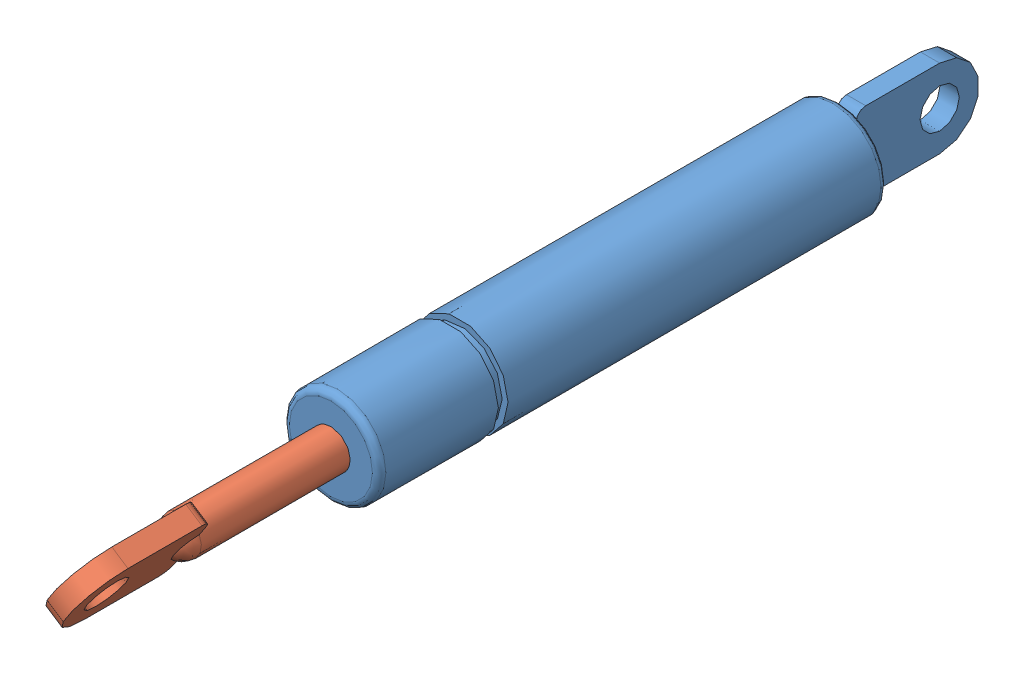
SolidWorks assembly gswb-4146-11_undefined, configuration Default. Lengths in mm.
Overall size (16.74 16.79 141.3).
2 component instances, 2 part files, 2 mates.
Components (placement in the parent):
- gswb-4146-11_undefined_01-1: gswb-4146-11_undefined_01 [Default] at (10.2534 -3.0103 7.33) size (15 15 99.1)
- gswb-4146-11_undefined_02-1: gswb-4146-11_undefined_02 [Default] at (10.2534 -3.0103 -9.5721) x (0.834638 -0.550799 0) z (0 0 1) size (12 12.2 84.6)
Mates (geometry in assembly coordinates):
- Concentric1: concentric anti-aligned: cylinder of gswb-4146-11_undefined_01-1 through (10.2534 -3.0103 8.33) axis (0 0 -1) radius 3; cylinder of gswb-4146-11_undefined_02-1 through (10.2534 -3.0103 33.4279) axis (0 0 1) radius 3
- LimitDistance1: limit distance = 36.5479 mm aligned: plane of gswb-4146-11_undefined_02-1 through (10.2534 -3.0103 -35.0721) normal (0 0 -1); plane of gswb-4146-11_undefined_01-1 through (10.2534 3.4397 -71.62) normal (0 0 -1)
